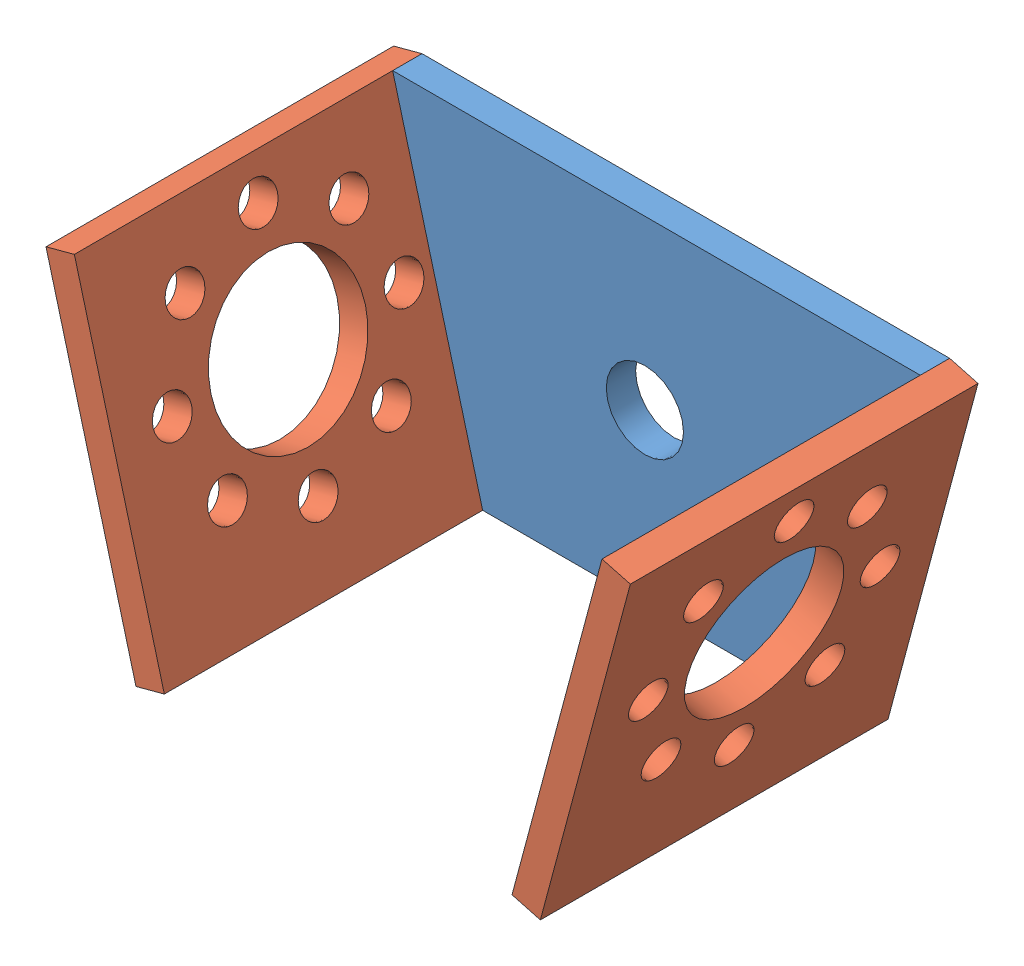
SolidWorks assembly Middle_hub_subassem, configuration Default. Lengths in mm.
Overall size (96.06 567.55 57.15).
3 component instances, 2 part files, 4 mates.
Components (placement in the parent):
- center_middle_hub-1: center_middle_hub [Default] at (63.6023 29.7357 53.5654) size (86.73 567.55 4.83)
- Left_right_middle_hub-1: Left_right_middle_hub [Default] at (26.6634 27.2017 62.7035) x (0.965926 0.258819 0) z (0 0 1) size (4.83 57.15 57.15)
- Left_right_middle_hub-2: Left_right_middle_hub [Default] at (99.6896 28.4508 62.7035) x (0.965926 -0.258819 0) z (0 0 1) size (4.83 57.15 57.15)
Mates (geometry in assembly coordinates):
- Coincident1: coincident aligned: line of center_middle_hub-1 through (36.9323 7.5239 53.5654) axis (-0.258819 0.965926 0); line of Left_right_middle_hub-1 through (36.9323 7.5239 53.5654) axis (-0.258819 0.965926 0)
- Coincident2: coincident: point of center_middle_hub-1; point of Left_right_middle_hub-1
- Coincident3: coincident aligned: line of center_middle_hub-1 through (94.0823 7.5239 53.5654) axis (0.258819 0.965926 0); line of Left_right_middle_hub-2 through (94.0823 7.5239 53.5654) axis (0.258819 0.965926 0)
- Coincident4: coincident: point of center_middle_hub-1; point of Left_right_middle_hub-2
